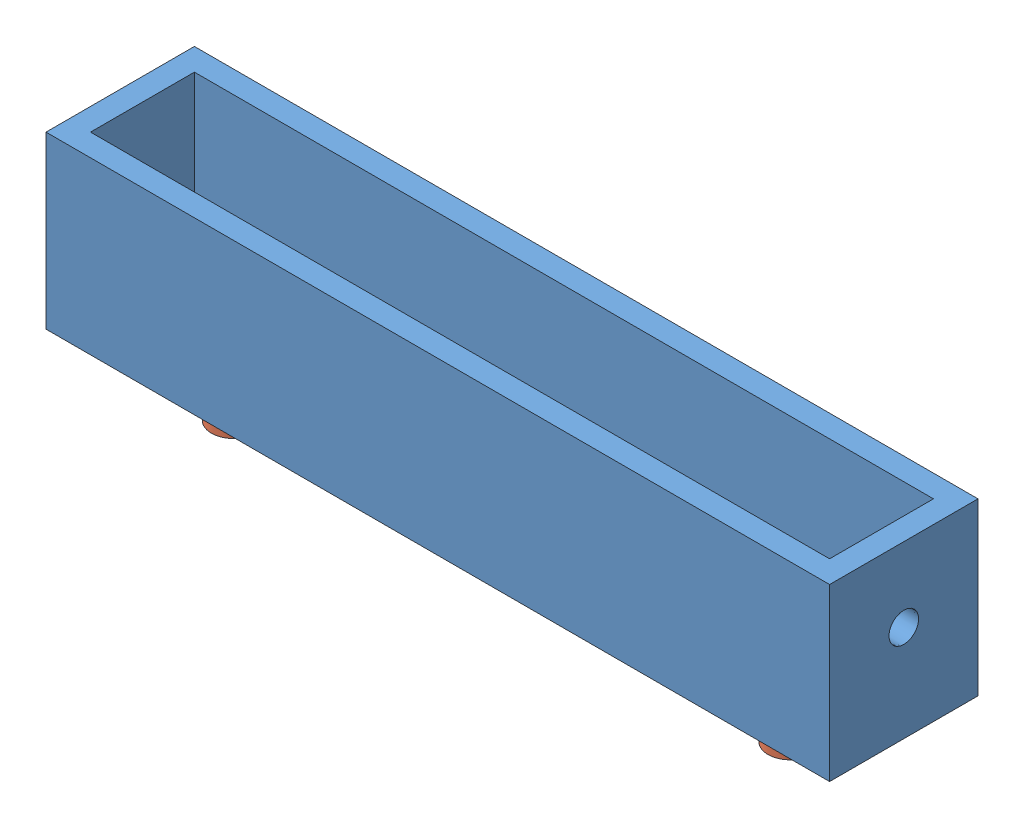
SolidWorks assembly 出绳点链接板（100）, configuration 默认. Lengths in mm.
Overall size (105.6 31 20).
3 component instances, 2 part files, 10 mates.
Components (placement in the parent):
- 出绳点链接板（100）-1: 出绳点链接板（100） [默认] at (-3.3008 48.9416 89.016) size (105.6 23 20)
- 柱塞螺丝M6-1: 柱塞螺丝M6 [默认] at (-40.8008 55.6816 89.016) x (-0.837169 0 -0.546944) z (-0.546944 0 0.837169) size (12 14.74 12)
- 柱塞螺丝M6-2: 柱塞螺丝M6 [默认] at (34.1992 55.6816 89.016) x (-0.837169 0 -0.546944) z (-0.546944 0 0.837169) size (12 14.74 12)
Mates (geometry in assembly coordinates):
- 同心1: concentric anti-aligned: cylinder of 出绳点链接板（100）-1 through (-40.8008 51.9416 89.016) axis (0 -1 0) radius 4; cylinder of 柱塞螺丝M6-1 through (-40.8008 48.9416 89.016) axis (0 1 0) radius 4
- 重合1: coincident anti-aligned: plane of 出绳点链接板（100）-1 through (-3.3008 51.9416 89.016) normal (0 1 0); plane of 柱塞螺丝M6-1 through (-40.8008 51.9416 89.016) normal (0 -1 0)
- 同心2: concentric anti-aligned: cylinder of 出绳点链接板（100）-1 through (34.1992 51.9416 89.016) axis (0 -1 0) radius 4; cylinder of 柱塞螺丝M6-2 through (34.1992 48.9416 89.016) axis (0 1 0) radius 4
- 重合2: coincident anti-aligned: plane of 出绳点链接板（100）-1 through (-3.3008 51.9416 89.016) normal (0 1 0); plane of 柱塞螺丝M6-2 through (34.1992 51.9416 89.016) normal (0 -1 0)
- 重合3: coincident anti-aligned: plane of 出绳点链接板（100）-1 through (49.4992 51.9416 89.016) normal (1 0 0); plane of 零件1^latest1-2 through (49.4992 61.9416 89.016) normal (-1 0 0)
- 同心3: concentric aligned: cylinder of 出绳点链接板（100）-1 through (53.8992 61.9416 89.016) axis (-1 0 0) radius 2; cylinder of 零件1^latest1-2 through (49.6992 61.9416 89.016) axis (-1 0 0) radius 1.5294
- 平行1: parallel anti-aligned: line of 出绳点链接板（100）-1 through (49.4992 71.9416 79.016) axis (0 -1 0); line of 零件1^latest1-2 through (51.6992 50.4649 89.0164) axis (0 1 0)
- 重合5: coincident anti-aligned: plane of 出绳点链接板（100）-1 through (-56.1008 51.9416 89.016) normal (-1 0 0); plane of 零件1^latest1-1 through (-56.1008 61.9416 89.016) normal (1 0 0)
- 同心4: concentric anti-aligned: cylinder of 出绳点链接板（100）-1 through (53.8992 61.9416 89.016) axis (-1 0 0) radius 2; cylinder of 零件1^latest1-1 through (-56.3008 61.9416 89.016) axis (1 0 0) radius 1.5294
- 平行2: parallel anti-aligned: line of 出绳点链接板（100）-1 through (-56.1008 71.9416 79.016) axis (0 -1 0); line of 零件1^latest1-1 through (-58.3008 50.4649 89.0156) axis (0 1 0)
